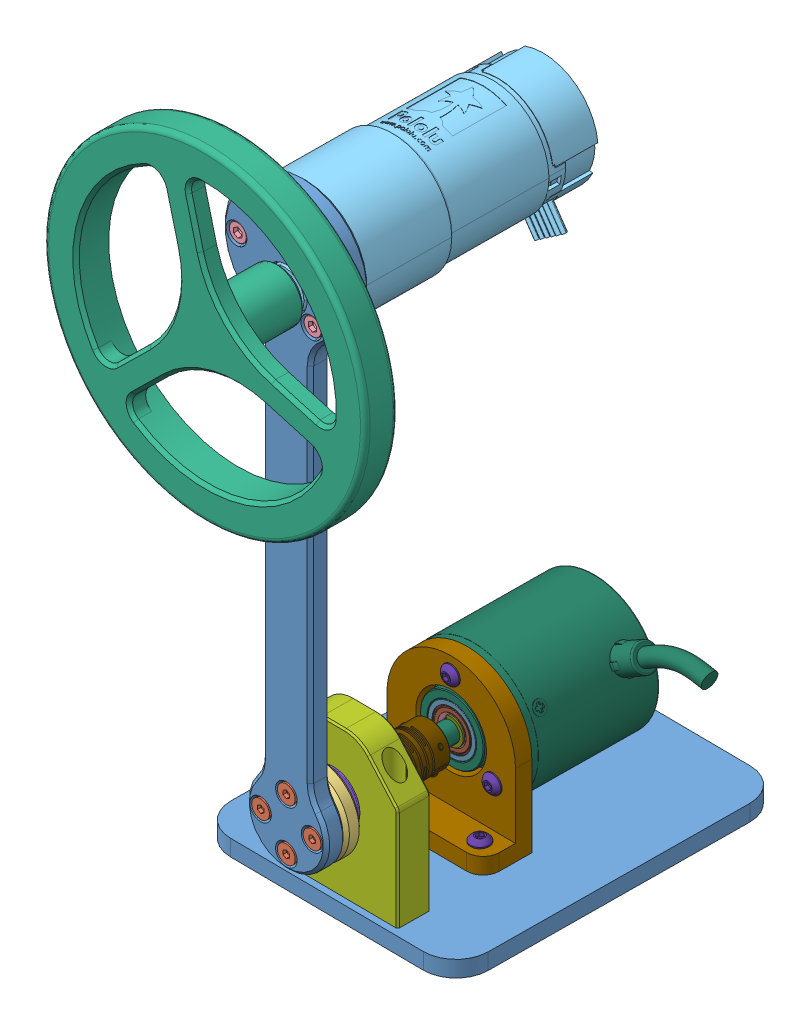
SolidWorks assembly Pendulum assembly, configuration Default. Lengths in mm.
Overall size (123.24 234.52 138.28).
37 component instances, 19 part files, 14 mates.
Components (placement in the parent):
- Pendulum Assem-1: Pendulum Assem [Default] at (0.0144 -0.016 2.0002) x (0.999999 0.001272 0) z (0 0.000011 1) size (40.28 182.55 94.92)
  - pendulum-1: pendulum [Default] at (12.3419 99.9999 36.7472) x (0.999961 -0.001272 0.008727) z (-0.008727 0 0.999962) size (40 182.5 6)
  - socket countersunk head screw_iso-1: socket countersunk head screw_iso [ISO 10642 - M3 x 12 - 12N] at (12.1839 17 42.746) x (0.008727 0 -0.999962) z (0.999952 0.00442 0.008726) size (12 5.54 5.54)
  - socket countersunk head screw_iso-2: socket countersunk head screw_iso [ISO 10642 - M3 x 12 - 12N] at (4.1944 25.0102 42.6763) x (0.008727 0 -0.999962) z (0.999918 0.00933 0.008726) size (12 5.54 5.54)
  - socket countersunk head screw_iso-3: socket countersunk head screw_iso [ISO 10642 - M3 x 12 - 12N] at (20.1938 24.9898 42.8159) x (0.008727 0 -0.999962) z (0.999932 0.007779 0.008726) size (12 5.54 5.54)
  - socket countersunk head screw_iso-4: socket countersunk head screw_iso [ISO 10642 - M3 x 12 - 12N] at (12.2043 33 42.7462) x (0.008727 0 -0.999962) z (0.999933 0.007608 0.008726) size (12 5.54 5.54)
  - Shaft-1: Shaft [Default] at (12.2465 25 36.7463) x (0.999961 -0.001272 0.008727) z (-0.008727 0 0.999962) size (25 25 27)
  - socket head cap screw_iso-1: socket head cap screw_iso [ISO 4762 M3 x 5 - 5N] at (4.6558 188.4331 42.2803) x (0.008727 0 -0.999962) z (0.999962 0 0.008727) size (8 5.5 5.5)
  - socket head cap screw_iso-2: socket head cap screw_iso [ISO 4762 M3 x 5 - 5N] at (4.6216 161.5864 42.28) x (0.008727 0 -0.999962) z (0.999962 0 0.008727) size (8 5.5 5.5)
  - socket head cap screw_iso-3: socket head cap screw_iso [ISO 4762 M3 x 5 - 5N] at (20.121 161.5666 42.4153) x (0.008727 0 -0.999962) z (0.999962 0 0.008727) size (8 5.5 5.5)
  - socket head cap screw_iso-4: socket head cap screw_iso [ISO 4762 M3 x 5 - 5N] at (27.8878 174.9802 42.483) x (0.008727 0 -0.999962) z (0.999962 0 0.008727) size (8 5.5 5.5)
  - socket head cap screw_iso-5: socket head cap screw_iso [ISO 4762 M3 x 5 - 5N] at (20.1552 188.4134 42.4156) x (0.008727 0 -0.999962) z (0.999962 0 0.008727) size (8 5.5 5.5)
  - socket head cap screw_iso-6: socket head cap screw_iso [ISO 4762 M3 x 5 - 5N] at (-3.111 175.0196 42.2125) x (0.008727 0 -0.999962) z (0.999962 0 0.008727) size (8 5.5 5.5)
  - 37d-gearmotor-100-131-150-encoder.step-1: 37d-gearmotor-100-131-150-encoder.step [Default] at (-7.3131 175.0252 16.6499) x (0.999961 -0.001272 0.008727) z (-0.008727 0 0.999962) size (36.88 41.23 94.6)
- Wheel-1: Wheel [Default] at (11.9585 168 69.7451) x (0.266605 0.963803 0.002327) z (0.008727 0 -0.999962) size (100 100 23)
- Bearing mount assem-1: Bearing mount assem [Default] at origin size (40.09 45 10.35)
  - bearing support-1: bearing support [Default] at (12.3023 0 30.3466) x (-0.999962 0 -0.008727) z (0.008727 0 -0.999962) size (40 45 10)
  - instrument ball bearing_68_am-1: instrument ball bearing_68_am [AFBMA 12.1.4.1 - 0050-16 - 8,SI,NC,8_68] at (12.3678 25 22.8468) x (0.008727 0 -0.999962) z (0.999962 0 0.008727) size (5 16 16)
  - instrument ball bearing_68_am-2: instrument ball bearing_68_am [AFBMA 12.1.4.1 - 0050-16 - 8,SI,NC,8_68] at (12.3241 25 27.8467) x (0.008727 0 -0.999962) z (0.999962 0 0.008727) size (5 16 16)
- Encoder mount-1: Encoder mount [Default] at (12.6601 25 -10.6519) x (0.999962 0 0.008727) z (-0.008727 0 0.999962) size (79.37 68.98 67.2)
  - encoder mount-1: encoder mount [Default] at origin size (40 45 15)
  - Enkoder YUMO E6B2-CWZ6C.stp-1: Enkoder YUMO E6B2-CWZ6C.stp [Default] at (0 0 4.8) x (-0.5 0.866025 0) z (0 0 1) size (40.1 68.5 58.4)
    - Łożysko 696.stp-1: Łożysko 696.stp [Default] x (0 0 -1) z (1 0 0) size (5 15 15)
      - bearing_696-zz_1_05.stp-1: bearing_696-zz_1_05.stp [Default] at origin size (0.3 12.3 12.3)
      - bearing_696-zz_1_04.stp-1: bearing_696-zz_1_04.stp [Default] at origin size (0.3 12.3 12.3)
      - bearing_696-zz_1_03.stp-1: bearing_696-zz_1_03.stp [Default] at origin size (3 13.5 13.5)
      - bearing_696-zz_1_02.stp-1: bearing_696-zz_1_02.stp [Default] at origin size (5 8.7 8.7)
      - bearing_696-zz_1_01.stp-1: bearing_696-zz_1_01.stp [Default] at origin size (5 15 15)
    - Enkoder YUMO E6B2-CWZ6C.stp-1: Enkoder YUMO E6B2-CWZ6C.stp [Default] at origin size (40.1 68.5 58.4)
    - Pierścień na wale enkodera YUMO.stp-1: Pierścień na wale enkodera YUMO.stp [Default] x (-0.782175 0.623059 0) z (0 0 1) size (8 5.8 0.5)
  - socket button head screw_iso-2: socket button head screw_iso [ISO 7380 - M3 x 10 - 10N] at (12.9904 -7.5 6.65) x (0 0 -1) z (1 0 0) size (11.65 5.7 5.7)
  - socket button head screw_iso-3: socket button head screw_iso [ISO 7380 - M3 x 10 - 10N] at (0 15 6.65) x (0 0 -1) z (1 0 0) size (11.65 5.7 5.7)
  - socket button head screw_iso-4: socket button head screw_iso [ISO 7380 - M3 x 10 - 10N] at (-12.9904 -7.5 6.65) x (0 0 -1) z (1 0 0) size (11.65 5.7 5.7)
  - 8011N214_Precision Flexible Shaft Coupling-1: 8011N214_Precision Flexible Shaft Coupling [8011N214] at (0 0 11.4) x (-0.334639 -0.942346 0) z (-0.942346 0.334639 0) size (13 16.8 13)
- stand-1: stand [Default] at (12.4594 0 12.3472) x (0.008727 0 -0.999962) z (0.999962 0 0.008727) size (100 5 80)
- socket button head screw_iso-1: socket button head screw_iso [ISO 7380 - M3 x 10 - 10N] at (26.5723 6.65 -0.5301) x (0 -1 0) z (-0.994225 0 -0.107319) size (11.65 5.7 5.7)
- socket button head screw_iso-2: socket button head screw_iso [ISO 7380 - M3 x 10 - 10N] at (-1.4266 6.65 -0.7744) x (0 -1 0) z (0 0 1) size (11.65 5.7 5.7)
Mates (geometry in assembly coordinates):
- Concentric381: concentric aligned: cylinder of Encoder mount-1/encoder mount-1 through (26.5723 5 -0.5301) axis (0 1 0) radius 1.7; cylinder of stand-1 through (26.5723 0 -0.5301) axis (0 1 0) radius 1.7
- Concentric391: concentric aligned: cylinder of Encoder mount-1/encoder mount-1 through (-1.4266 5 -0.7744) axis (0 1 0) radius 1.7; cylinder of stand-1 through (-1.4266 0 -0.7744) axis (0 1 0) radius 1.7
- Coincident291: coincident anti-aligned: plane of Encoder mount-1/encoder mount-1 through (-7.47 0 4.173) normal (0 -1 0); plane of stand-1 through (12.4594 0 12.3472) normal (0 1 0)
- Concentric401: concentric aligned: cylinder of Bearing mount assem-1/bearing support-1 through (26.3454 45 25.4689) axis (0 1 0) radius 1.7; cylinder of stand-1 through (26.3454 0 25.4689) axis (0 1 0) radius 1.7
- Concentric411: concentric aligned: cylinder of Bearing mount assem-1/bearing support-1 through (-1.6535 45 25.2246) axis (0 1 0) radius 1.7; cylinder of stand-1 through (-1.6535 0 25.2246) axis (0 1 0) radius 1.7
- Coincident301: coincident anti-aligned: plane of Bearing mount assem-1/bearing support-1 through (12.3896 0 20.3469) normal (0 -1 0); plane of stand-1 through (12.4594 0 12.3472) normal (0 1 0)
- Concentric421: concentric aligned: cylinder of Pendulum Assem-1/Shaft-1 through (12.4646 25 11.7473) axis (0.008727 0 -0.999962) radius 3; cylinder of Bearing mount assem-1/instrument ball bearing_68_am-2 through (12.144 25 48.4834) axis (0.008727 0 -0.999962) radius 2.5
- Distance11: distance = 3 mm anti-aligned: plane of Pendulum Assem-1/Shaft-1 through (12.4646 28 11.7473) normal (0.008727 0 -0.999962); plane of Encoder mount-1/Enkoder YUMO E6B2-CWZ6C.stp-1/Enkoder YUMO E6B2-CWZ6C.stp-1 through (12.4908 25 8.7474) normal (-0.008727 0 0.999962)
- Concentric431: concentric anti-aligned: cylinder of Pendulum Assem-1/37d-gearmotor-100-131-150-encoder.step-1 through (12.037 168 60.7454) axis (0.008727 0 -0.999962) radius 3; cylinder of Wheel-1 through (12.1592 168 46.7459) axis (-0.008727 0 0.999962) radius 3
- Distance21: distance = 4 mm anti-aligned: plane of Pendulum Assem-1/37d-gearmotor-100-131-150-encoder.step-1 through (12.037 168 60.7454) normal (-0.008727 0 0.999962); plane of Wheel-1 through (12.0021 168 64.7453) normal (0.008727 0 -0.999962)
- Concentric451: concentric aligned: cylinder of Encoder mount-1/encoder mount-1 through (26.5723 5 -0.5301) axis (0 1 0) radius 1.7; cylinder of socket button head screw_iso-1 through (26.5723 6.65 -0.5301) axis (0 1 0) radius 1.5
- Coincident331: coincident anti-aligned: plane of Encoder mount-1/encoder mount-1 through (-7.47 5 4.173) normal (0 1 0); plane of socket button head screw_iso-1 through (26.4113 5 0.9613) normal (0 -1 0)
- Concentric461: concentric aligned: cylinder of Encoder mount-1/encoder mount-1 through (-1.4266 5 -0.7744) axis (0 1 0) radius 1.7; cylinder of socket button head screw_iso-2 through (-1.4266 6.65 -0.7744) axis (0 1 0) radius 1.5
- Coincident341: coincident anti-aligned: plane of Encoder mount-1/encoder mount-1 through (-7.47 5 4.173) normal (0 1 0); plane of socket button head screw_iso-2 through (0.0734 5 -0.7744) normal (0 -1 0)
